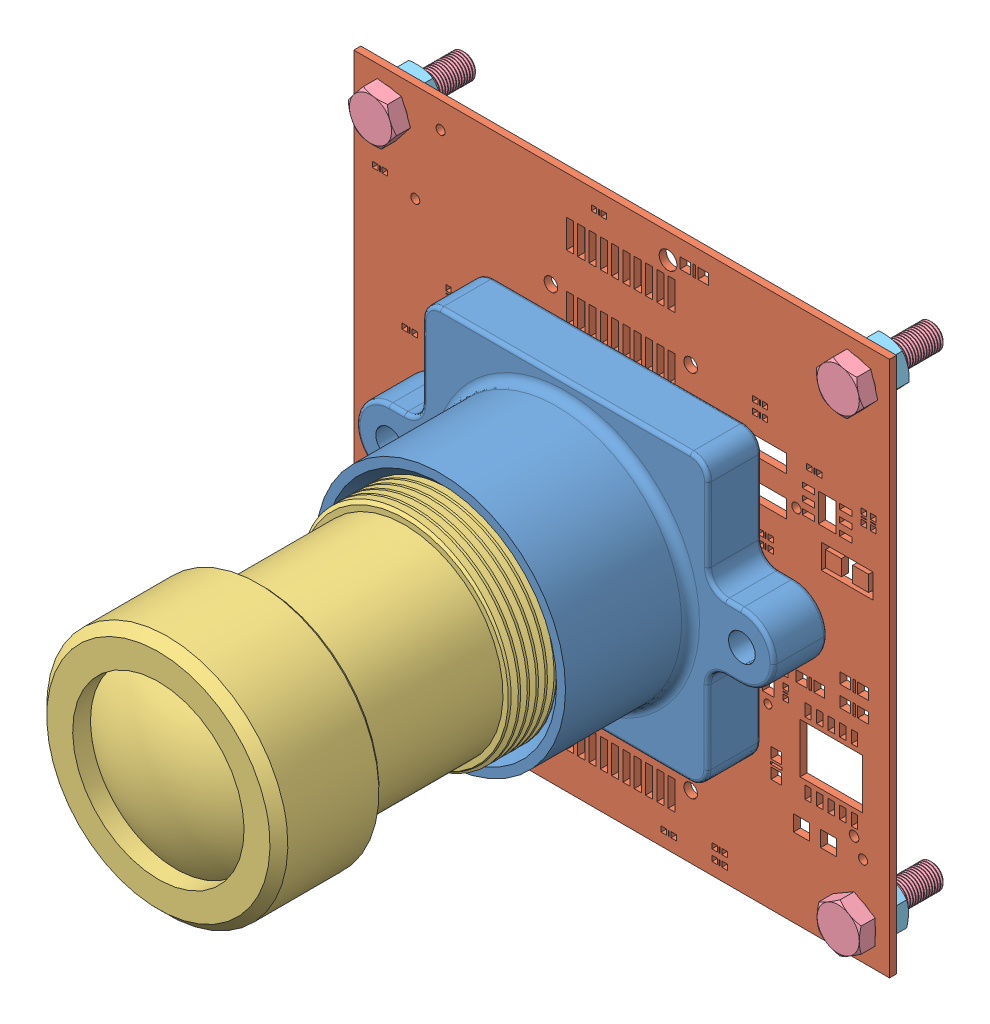
SolidWorks assembly CamAssembly, configuration Default. Lengths in mm.
Overall size (762 762 778.02).
11 component instances, 5 part files, 20 mates.
Components (placement in the parent):
- LensHolder-1: LensHolder [Default] at (-187.3903 -52.6275 -270.5661) x (0.999996 -0.00277 0) z (0 0 1) size (593.75 406.18 254)
- Part1-1: Part1 [Default] at (-564.7795 -431.2394 -280.5661) size (762 762 10)
- Lens-1: Lens [Default] at (-187.3903 -52.6275 -194.3661) x (0.980958 0.194219 0) z (0 0 1) size (342.9 342.9 591.82)
- heavy hex screw_am-1: heavy hex screw_am [B18.2.3.3M - Heavy hex screw, M36 x 4.0 x 110 --78S] at (147.6051 -384.0549 -247.1861) x (0 0 -1) z (1 0 0) size (133.38 69.28 60)
- hex nut heavy_am-1: hex nut heavy_am [B18.2.4.6M - Heavy hex nut,  M36 x 4 --D-S] at (147.6051 -384.0549 -280.5661) size (60 69.28 36.6)
- hex nut heavy_am-2: hex nut heavy_am [B18.2.4.6M - Heavy hex nut,  M36 x 4 --D-S] at (-517.595 -384.0549 -280.5661) x (0.987351 0.158553 0) z (0 0 1) size (60 69.28 36.6)
- heavy hex screw_am-2: heavy hex screw_am [B18.2.3.3M - Heavy hex screw, M36 x 4.0 x 110 --78S] at (-517.595 -384.0549 -247.1861) x (0 0 -1) z (0.987351 0.158553 0) size (133.38 69.28 60)
- hex nut heavy_am-3: hex nut heavy_am [B18.2.4.6M - Heavy hex nut,  M36 x 4 --D-S] at (147.6051 281.1452 -280.5661) x (0.959125 0.282984 0) z (0 0 1) size (60 69.28 36.6)
- heavy hex screw_am-3: heavy hex screw_am [B18.2.3.3M - Heavy hex screw, M36 x 4.0 x 110 --78S] at (147.6051 281.1452 -247.1861) x (0 0 -1) z (0.959125 0.282984 0) size (133.38 69.28 60)
- hex nut heavy_am-4: hex nut heavy_am [B18.2.4.6M - Heavy hex nut,  M36 x 4 --D-S] at (-517.595 281.1452 -280.5661) x (0.928571 0.371154 0) z (0 0 1) size (60 69.28 36.6)
- heavy hex screw_am-4: heavy hex screw_am [B18.2.3.3M - Heavy hex screw, M36 x 4.0 x 110 --78S] at (-517.595 281.1452 -247.1861) x (0 0 -1) z (0.928571 0.371154 0) size (133.38 69.28 60)
Mates (geometry in assembly coordinates):
- Concentric3: concentric anti-aligned: cylinder of LensHolder-1 through (-187.3903 -52.6275 -625.4184) axis (0 0 1) radius 152.4; cylinder of Lens-1 through (-187.3903 -52.6275 237.4339) axis (0 0 -1) radius 139.7
- Coincident5: coincident anti-aligned: plane of LensHolder-1 through (-188.1856 -52.1474 -194.3661) normal (0 0 1); plane of Lens-1 through (-187.3903 -52.6275 -194.3661) normal (0 0 -1)
- Concentric5: concentric aligned: cylinder of heavy hex screw_am-1 through (147.6051 -384.0549 -247.1861) axis (0 0 1) radius 18; cone of hex nut heavy_am-1 through (147.6051 -384.0549 -313.4858) axis (0 0 1)
- Coincident8: coincident anti-aligned: plane of Part1-1 through (-564.7795 -431.2394 -280.5661) normal (0 0 -1); plane of hex nut heavy_am-1 through (87.6051 -384.0549 -280.5661) normal (0 0 1)
- Concentric6: concentric aligned: cone of hex nut heavy_am-2 through (-517.595 -384.0549 -313.4858) axis (0 0 1); cylinder of heavy hex screw_am-2 through (-517.595 -384.0549 -247.1861) axis (0 0 1) radius 18
- Coincident11: coincident anti-aligned: plane of Part1-1 through (-564.7795 -431.2394 -280.5661) normal (0 0 -1); plane of hex nut heavy_am-2 through (-576.8361 -393.5681 -280.5661) normal (0 0 1)
- Concentric9: concentric aligned: cone of hex nut heavy_am-3 through (147.6051 281.1452 -313.4858) axis (0 0 1); cylinder of heavy hex screw_am-3 through (147.6051 281.1452 -247.1861) axis (0 0 1) radius 18
- Coincident13: coincident anti-aligned: plane of Part1-1 through (-564.7795 -431.2394 -280.5661) normal (0 0 -1); plane of hex nut heavy_am-3 through (90.0576 264.1662 -280.5661) normal (0 0 1)
- Concentric11: concentric aligned: cone of hex nut heavy_am-4 through (-517.595 281.1452 -313.4858) axis (0 0 1); cylinder of heavy hex screw_am-4 through (-517.595 281.1452 -247.1861) axis (0 0 1) radius 18
- Coincident15: coincident anti-aligned: plane of Part1-1 through (-564.7795 -431.2394 -280.5661) normal (0 0 -1); plane of hex nut heavy_am-4 through (-573.3093 258.8759 -280.5661) normal (0 0 1)
- Coincident16: coincident anti-aligned: plane of LensHolder-1 through (-438.1853 -51.4549 -270.5661) normal (0 0 -1); plane of Part1-1 through (-564.7795 -431.2394 -270.5661) normal (0 0 1)
- Coincident17: coincident anti-aligned: plane of Part1-1 through (-564.7795 -431.2394 -270.5661) normal (0 0 1); plane of heavy hex screw_am-4 through (-530.4522 313.3118 -270.5661) normal (0 0 -1)
- Coincident18: coincident anti-aligned: plane of Part1-1 through (-564.7795 -431.2394 -270.5661) normal (0 0 1); plane of heavy hex screw_am-3 through (137.8022 314.3702 -270.5661) normal (0 0 -1)
- Concentric12: concentric anti-aligned: circle of Part1-1; circle of heavy hex screw_am-3
- Concentric13: concentric anti-aligned: cylinder of Part1-1 through (-517.595 281.1452 -130.5661) axis (0 0 -1) radius 12.7; circle of heavy hex screw_am-4
- Concentric14: concentric anti-aligned: cylinder of LensHolder-1 through (-438.1853 -51.4549 -270.5661) axis (0 0 1) radius 19.05; cylinder of Part1-1 through (-438.1853 -51.4549 -130.5661) axis (0 0 -1) radius 34.915
- Coincident19: coincident anti-aligned: plane of Part1-1 through (-564.7795 -431.2394 -270.5661) normal (0 0 1); plane of heavy hex screw_am-1 through (147.6051 -349.4139 -270.5661) normal (0 0 -1)
- Concentric16: concentric aligned: circle of Part1-1; circle of heavy hex screw_am-1
- Concentric17: concentric anti-aligned: cylinder of Part1-1 through (-517.595 -384.0549 -130.5661) axis (0 0 -1) radius 12.7; circle of heavy hex screw_am-2
- Coincident22: coincident anti-aligned: plane of Part1-1 through (-564.7795 -431.2394 -270.5661) normal (0 0 1); plane of heavy hex screw_am-2 through (-523.0875 -349.8521 -270.5661) normal (0 0 -1)
